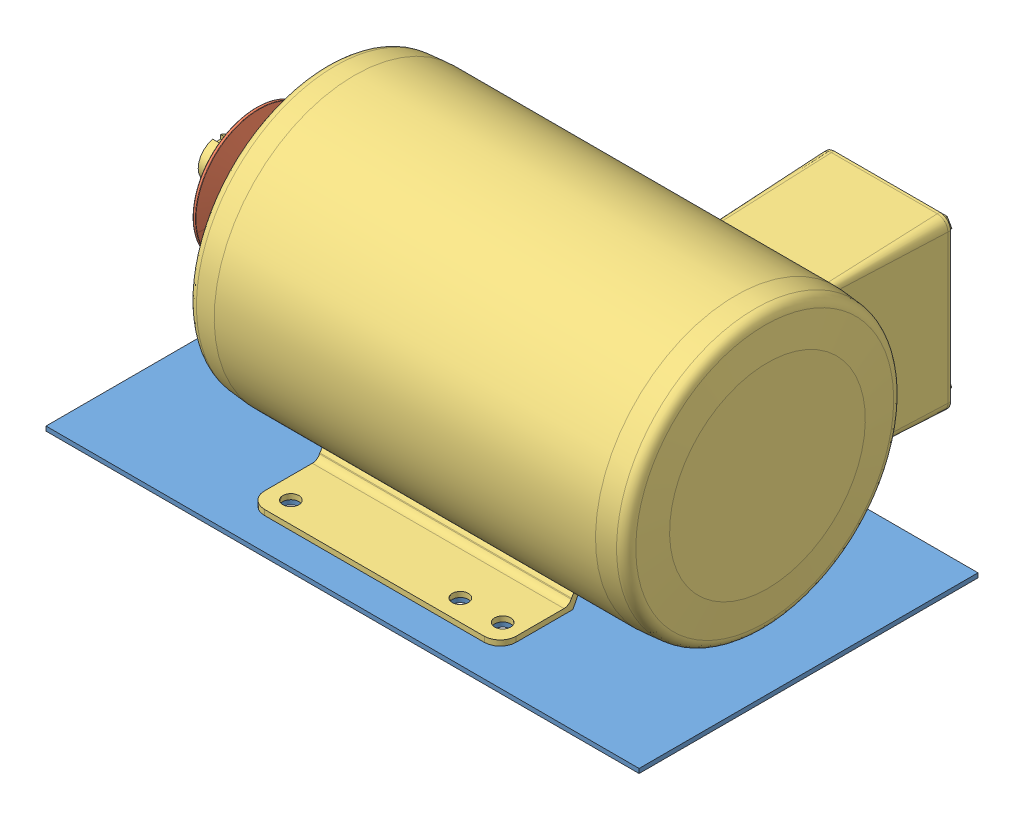
SolidWorks assembly Motor Assembly, configuration Default. Lengths in mm.
Overall size (355.6 175.63 244.09).
3 component instances, 3 part files, 6 mates.
Components (placement in the parent):
- Motor Base-1: Motor Base [Default] at (-72.8682 166.1231 394.6609) size (355.6 2.66 203.2)
- Motor Pulley-1: Motor Pulley [Default] at (-20.5124 224.7511 312.9655) x (0 0.979314 0.202344) z (-1 0 0) size (76.2 76.2 27.17)
- Motor-1: Motor [Default] at (-72.1062 255.0231 293.0609) x (0 0 1) z (-1 0 0) size (226.57 172.97 330.2)
Mates (geometry in assembly coordinates):
- Coincident1: coincident anti-aligned: plane of Motor Base-1 through (-72.8682 166.1231 394.6609) normal (0 1 0); plane of Motor-1 through (170.8448 166.1231 366.0859) normal (0 -1 0)
- Parallel1: parallel aligned: line of Motor Base-1 through (-72.8682 166.1231 394.6609) axis (1 0 0); line of Motor-1 through (39.0188 169.2981 375.6109) axis (1 0 0)
- Concentric1: concentric anti-aligned: cylinder of motor pulley-1 through (-125.2874 255.0231 293.0609) axis (1 0 0) radius 11.1125; cylinder of Motor-1 through (-72.1062 255.0231 293.0609) axis (-1 0 0) radius 11.1125
- Coincident6: coincident: plane of motor pulley-1 through (-59.4062 255.0231 293.0609) normal (-1 0 0); line of Motor-1 through (-59.4062 266.1356 293.0609) axis (0 -1 0)
- Coincident7: coincident aligned: line of Motor Base-1 through (104.9318 166.1231 191.4609) axis (0 0 1); line of Motor-1 through (104.9318 166.1231 210.5109) axis (0 0 1)
- Coincident8: coincident aligned: line of Motor Base-1 through (-72.8682 166.1231 293.0609) axis (1 0 0); line of Motor-1 through (30.5695 166.1231 293.0609) axis (1 0 0)
